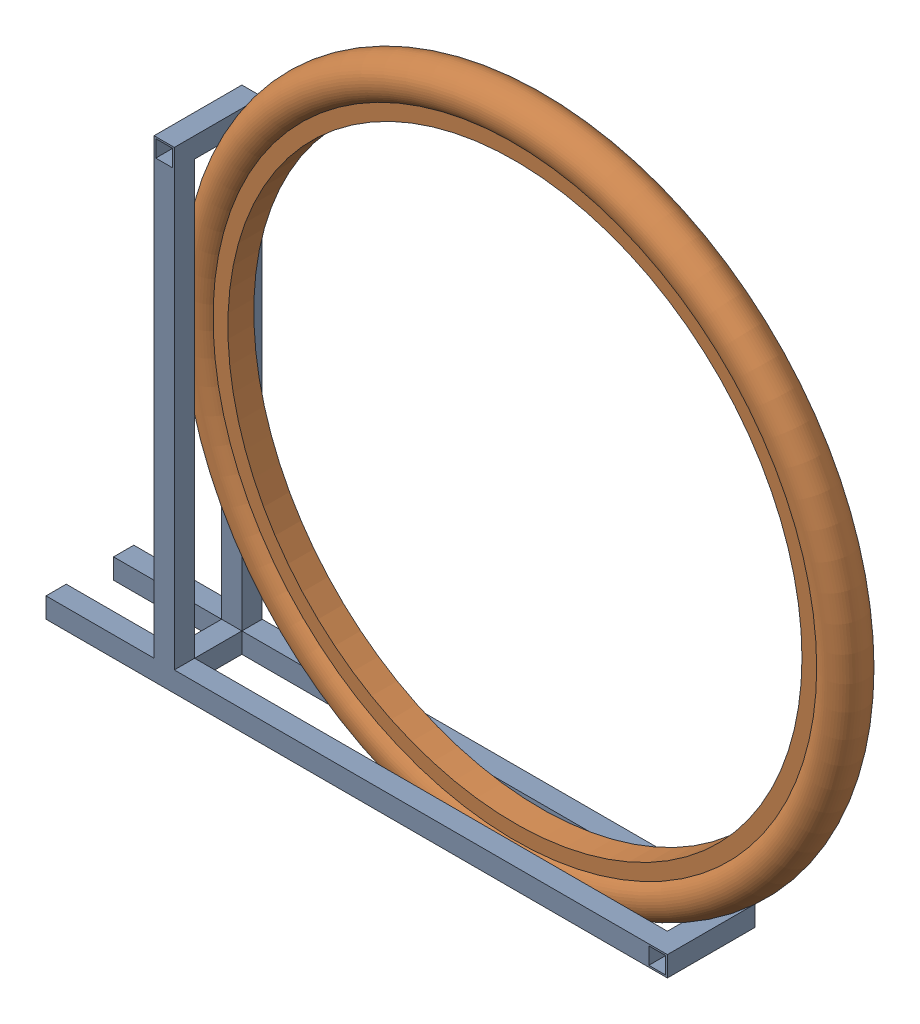
SolidWorks assembly EnsamblajeBaseGomaBicicleta, configuration Predeterminado. Lengths in mm.
Overall size (729.27 635 82.55).
2 component instances, 2 part files, 1 mates.
Components (placement in the parent):
- SoporteBicicleta-1: SoporteBicicleta [Predeterminado] at (-248.6949 -12.6627 -31.75) size (584.2 444.5 82.55)
- DiametroGomaConAroBicicleta-1: DiametroGomaConAroBicicleta [Predeterminado] at (42.424 263.2671 0) size (635 635 38.1)
Mates (geometry in assembly coordinates):
- Distancia2: distance = 10.033 mm anti-aligned: plane of SoporteBicicleta-1 through (-248.6949 -12.6627 -22.225) normal (0 0 1); plane of DiametroGomaConAroBicicleta-1 through (42.424 533.1421 -12.192) normal (0 0 -1)
